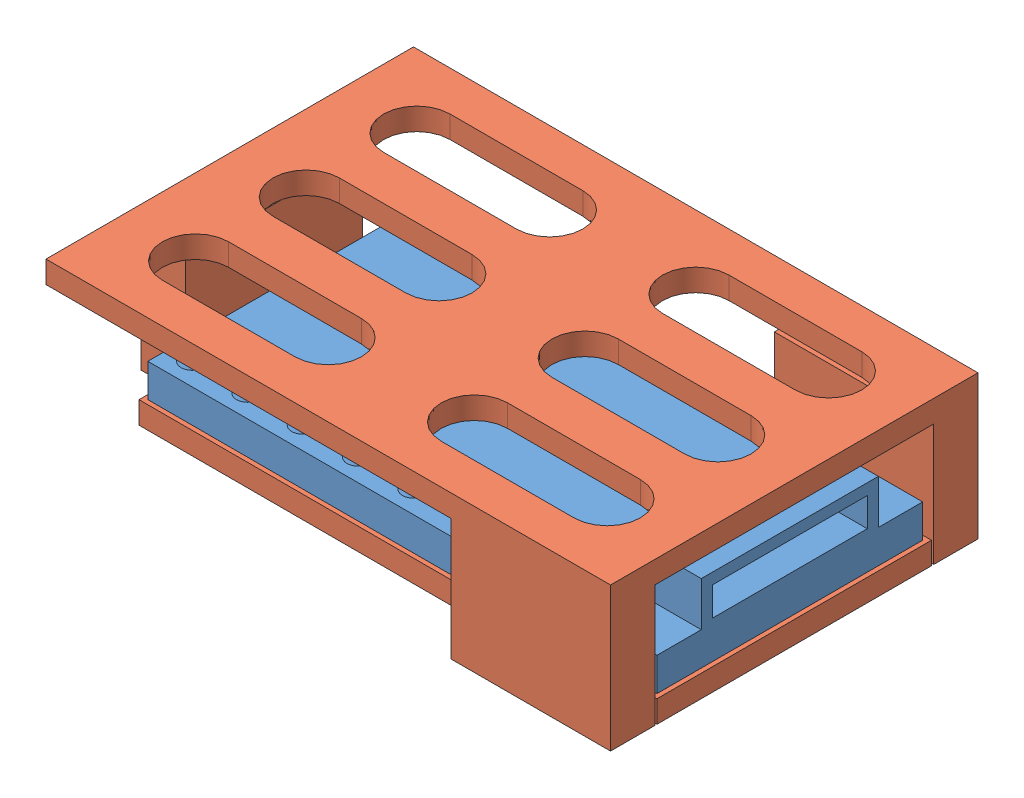
SolidWorks assembly encoder_motor_driver_asm, configuration Default. Lengths in mm.
Overall size (25.5 6.5 16.6).
2 component instances, 2 part files, 4 mates.
Components (placement in the parent):
- encoder_motor_driver-1: encoder_motor_driver [Default] at origin size (23 3.5 12)
- Part2^encoder_motor_driver_asm-1: Part2^encoder_motor_driver_asm [Default] x (-1 0 0) z (0 -1 0) size (25.5 16.6 6.5) (virtual)
Mates (geometry in assembly coordinates):
- InPlace1: in place: plane of encoder_motor_driver-1 through (0 0 0) normal (0 -1 0); plane of Part2^encoder_motor_driver_asm-1 through (0 0 0) normal (0 -1 0); moOrthogonalPlaneRef_w of encoder_motor_driver-1 through (0 0 0) normal (0 -1 0); plane of Part2^encoder_motor_driver_asm-1 through (0 0 0) normal (0 0 -1); plane of encoder_motor_driver-1 through (0 0 0) normal (0 -1 0); plane of Part2^encoder_motor_driver_asm-1 through (0 0 0) normal (-1 0 0); plane of encoder_motor_driver-1 through (0 0 0) normal (0 -1 0); unknown of Part2^encoder_motor_driver_asm-1
- Coincident1: coincident aligned: plane of encoder_motor_driver-1; plane of Part2^encoder_motor_driver_asm-1
- Coincident2: coincident aligned: moOrthogonalPlaneRef_w of encoder_motor_driver-1 through (0 0 0) normal (0 0 -1); plane of Part2^encoder_motor_driver_asm-1 through (0 0 0) normal (0 0 -1)
- Coincident3: coincident anti-aligned: moOrthogonalPlaneRef_w of encoder_motor_driver-1 through (0 0 0) normal (1 0 0); plane of Part2^encoder_motor_driver_asm-1 through (0 0 0) normal (-1 0 0)
